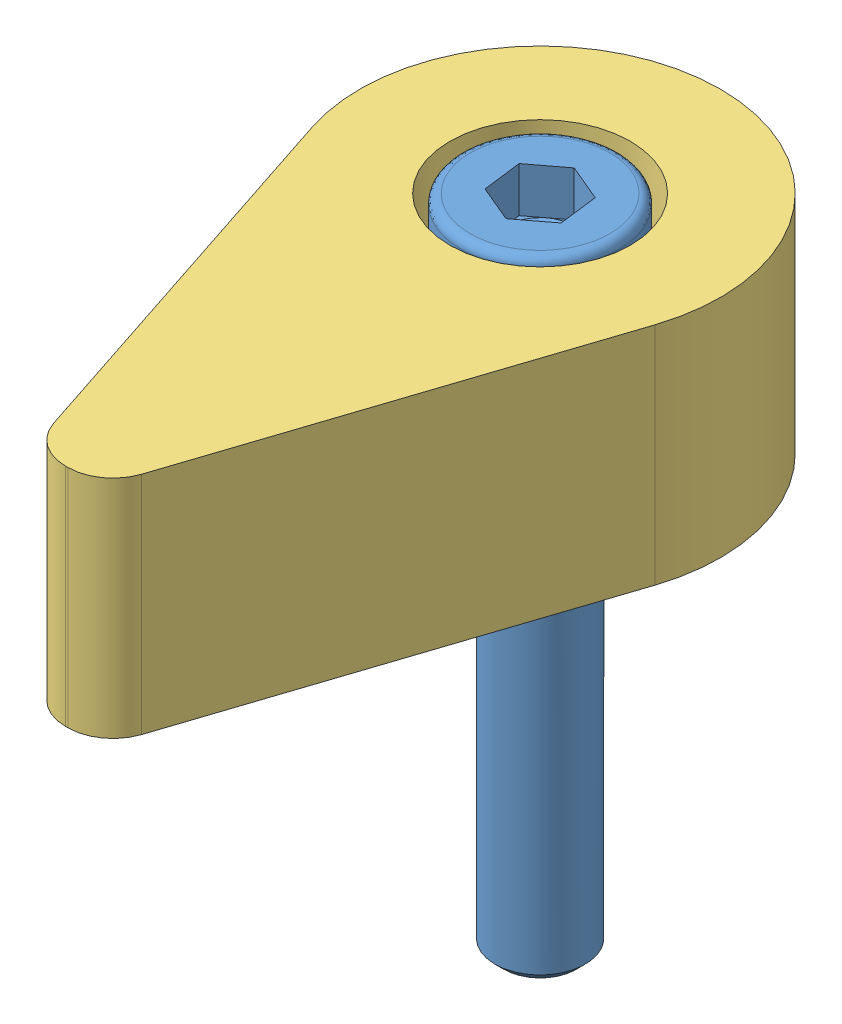
SolidWorks assembly flag_screw, configuration По умолчанию. Lengths in mm.
Overall size (16 29 29).
4 component instances, 4 part files, 6 mates.
Components (placement in the parent):
- flag-1: flag [По умолчанию] at (-48.2962 13.0906 23.7085) size (16 10 29) (hidden)
- socket head cap screw_din_1-1: socket head cap screw_din_1 [DIN 912 M4 x 25 --- 25N] at (-48.2962 23.0906 23.7085) x (0 -1 0) z (-0.387543 0 0.921852) size (29 7 7)
- plain washer 6902 type abc_din-1: plain washer 6902 type abc_din [DIN 6902-A4.55] at (-48.2962 13.0906 23.7085) x (0 -1 0) z (-0.000413 0 1) size (1 10 10)
- flag_drop-1: flag_drop [По умолчанию] at (-48.2962 13.0906 23.7085) x (1 0 0) z (0 1 0) size (16 29 10)
Mates (geometry in assembly coordinates):
- Концентричный1: concentric aligned: cylinder of socket head cap screw_din_1-1 through (-48.2962 54.8406 23.7085) axis (0 1 0) radius 3.5; cylinder of flag-1 through (-48.2962 19.0906 23.7085) axis (0 1 0) radius 4
- Концентричный2: concentric aligned: cylinder of socket head cap screw_din_1-1 through (-48.2962 54.8406 23.7085) axis (0 1 0) radius 2; cylinder of plain washer 6902 type abc_din-1 through (-48.2962 12.0906 23.7085) axis (0 1 0) radius 2.275
- Совпадение2: coincident anti-aligned: plane of flag-1 through (-48.2962 13.0906 23.7085) normal (0 -1 0); plane of plain washer 6902 type abc_din-1 through (-48.2962 13.0906 23.7085) normal (0 1 0)
- Совпадение3: coincident anti-aligned: plane of flag-1 through (-48.2962 19.0906 23.7085) normal (0 1 0); plane of socket head cap screw_din_1-1 through (-45.0697 19.0906 25.0649) normal (0 -1 0)
- Концентричный3: concentric aligned: cylinder of socket head cap screw_din_1-1 through (-48.2962 54.8406 23.7085) axis (0 1 0) radius 2; cylinder of flag_drop-1 through (-48.2962 19.0906 23.7085) axis (0 1 0) radius 1.65
- Совпадение4: coincident anti-aligned: plane of socket head cap screw_din_1-1 through (-45.0697 19.0906 25.0649) normal (0 -1 0); plane of flag_drop-1 through (-48.2962 19.0906 23.7085) normal (0 1 0)
